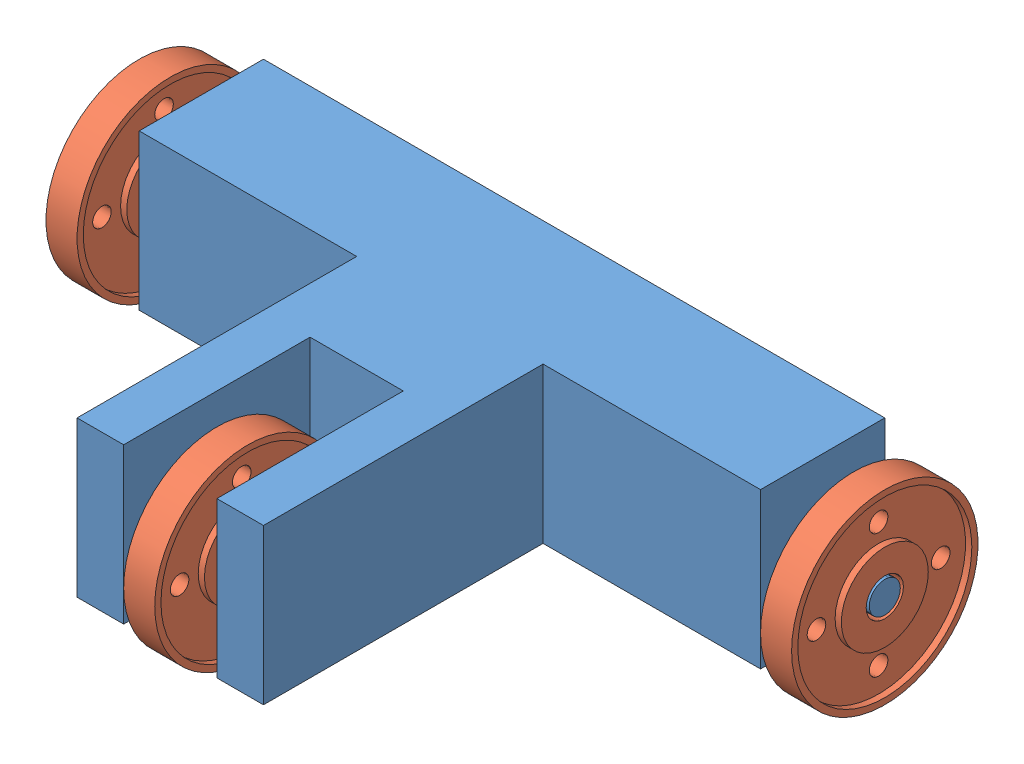
SolidWorks assembly Assy_WheelRobot, configuration Default. Lengths in mm.
Overall size (120 30 75).
4 component instances, 2 part files, 9 mates.
Components (placement in the parent):
- Platform-1: Platform [Default] at origin size (120 25 65)
- Wheel-1: Wheel [Default] at (-57.5 10 -10) x (0 -1 0) z (0 0 1) size (30 5 30)
- Wheel-2: Wheel [Default] at (57.5 10 -10) x (0 -1 0) z (0 0 -1) size (30 5 30)
- Wheel-4: Wheel [Default] at (0 10 35) x (0 -1 0) z (0 0 -1) size (30 5 30)
Mates (geometry in assembly coordinates):
- Concentric1: concentric: cylinder of Platform-1 through (-60 10 -10) axis (1 0 0) radius 2.5; cylinder of Wheel-1 through (-55 10 -10) axis (-1 0 0) radius 3
- Parallel1: parallel anti-aligned: plane of Wheel-1; plane of assembly through (0 0 0) normal (0 1 0)
- Coincident2: coincident aligned: plane of Platform-1 through (-60 10 -10) normal (-1 0 0); plane of Wheel-1 through (-60 10 -10) normal (-1 0 0)
- Concentric2: concentric anti-aligned: cylinder of Platform-1 through (60 10 -10) axis (-1 0 0) radius 2.5; cylinder of Wheel-2 through (55 10 -10) axis (1 0 0) radius 3
- Parallel2: parallel anti-aligned: plane of Wheel-2; plane of assembly through (0 0 0) normal (0 1 0)
- Coincident3: coincident aligned: plane of Platform-1 through (60 10 -10) normal (1 0 0); plane of Wheel-2 through (60 10 -10) normal (1 0 0)
- Concentric3: concentric anti-aligned: cylinder of Platform-1 through (500000 10 35) axis (-1 0 0) radius 2.5; cylinder of Wheel-4 through (-2.5 10 35) axis (1 0 0) radius 3
- Width1: width anti-aligned: plane of Wheel-4 through (2.5 10 35) normal (1 0 0); plane of Wheel-4 through (-2.5 10 35) normal (-1 0 0); plane of Platform-1 through (7.5 0 15) normal (-1 0 0); plane of Platform-1 through (-7.5 0 15) normal (1 0 0)
- Parallel4: parallel anti-aligned: plane of Wheel-4; plane of assembly
